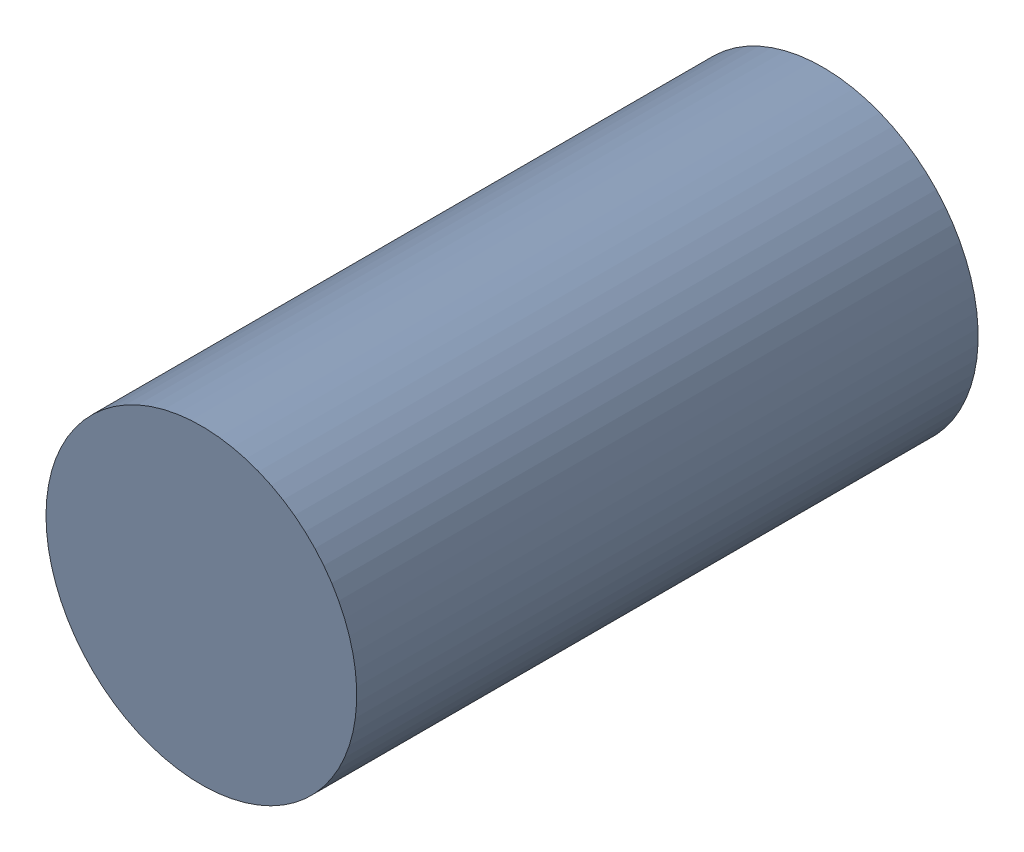
SolidWorks assembly MH9, configuration Default. Lengths in mm.
Overall size (1 1 2).
2 component instances, 1 part files, 0 mates.
Components (placement in the parent):
- 11929539264-1: 11929539264 [Default] at (59.1753 107.3366 -1.5) x (-1 0 0) z (0 0 1) size (1 1 2)
  - Cylinder-1: Cylinder [Default] at origin size (1 1 2)
